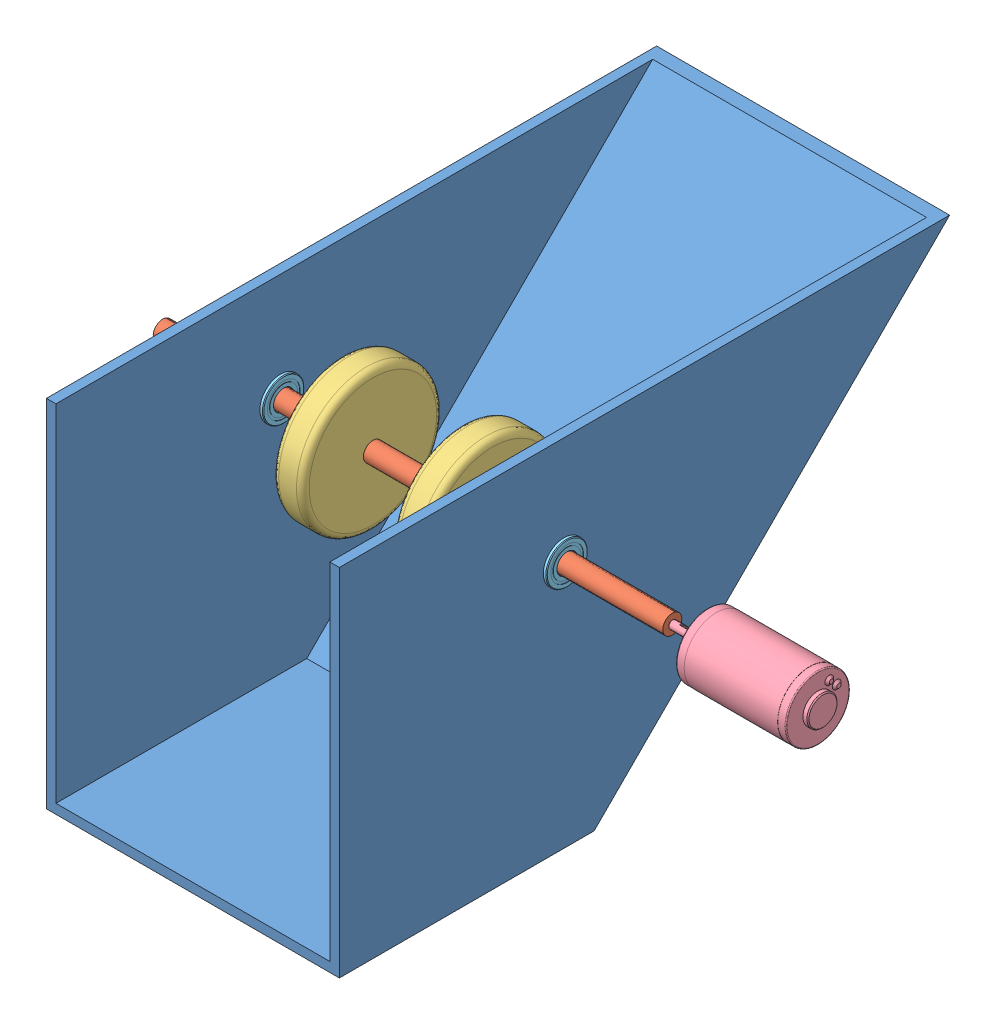
SolidWorks assembly Launcher1, configuration Default. Lengths in mm.
Overall size (658.2 354.41 608.41).
7 component instances, 5 part files, 12 mates.
Components (placement in the parent):
- WheelAndSurfaceBase-1: WheelAndSurfaceBase [Default] at origin size (292.1 354.41 608.41)
- LauncherAxel-1: LauncherAxel [Default] at (0 56.9612 93.5173) x (0 0.196579 -0.980488) z (0 0.980488 0.196579) size (19 508 19)
- 5.5Wheel-1: 5.5Wheel [Default] at (-59.69 56.9612 93.5173) x (0 0.971322 0.237769) z (0 -0.237769 0.971322) size (139.7 30.48 139.7)
- 5.5Wheel-2: 5.5Wheel [Default] at (59.69 56.9612 93.5173) x (0 0.997812 -0.066119) z (0 0.066119 0.997812) size (139.7 30.48 139.7)
- CIM-217-2000-3580300-1: CIM-217-2000-3580300 [Default] at (289.6 56.9612 93.5173) size (150.2 64.01 64.01)
- FlangeBearing-1: FlangeBearing [6384K367] at (-140.4938 56.9612 93.5173) x (0 0 -1) z (1 0 0) size (44.45 44.45 14.29)
- FlangeBearing-3: FlangeBearing [6384K367] at (142.0812 56.9612 93.5173) x (0 0 -1) z (1 0 0) size (44.45 44.45 14.29)
Mates (geometry in assembly coordinates):
- Concentric1: concentric anti-aligned: cylinder of LauncherAxel-1 through (-254 56.9612 93.5173) axis (1 0 0) radius 9.4996; cylinder of 5.5Wheel-1 through (-44.45 56.9612 93.5173) axis (-1 0 0) radius 9.525
- Concentric2: concentric anti-aligned: cylinder of LauncherAxel-1 through (-254 56.9612 93.5173) axis (1 0 0) radius 9.4996; cylinder of 5.5Wheel-2 through (74.93 56.9612 93.5173) axis (-1 0 0) radius 9.525
- Concentric8: concentric anti-aligned: cylinder of WheelAndSurfaceBase-1 through (368.046 56.9612 93.5173) axis (-1 0 0) radius 20.6375; cylinder of LauncherAxel-1 through (-254 56.9612 93.5173) axis (1 0 0) radius 9.4996
- Distance1: distance = 88.9 mm anti-aligned: plane of 5.5Wheel-1 through (-44.45 56.9612 93.5173) normal (1 0 0); plane of 5.5Wheel-2 through (44.45 56.9612 93.5173) normal (-1 0 0)
- Width1: width aligned: plane of WheelAndSurfaceBase-1 through (136.525 190.5 317.5) normal (-1 0 0); plane of WheelAndSurfaceBase-1 through (-136.525 190.5 317.5) normal (1 0 0); plane of 5.5Wheel-1 through (-74.93 56.9612 93.5173) normal (-1 0 0); plane of 5.5Wheel-2 through (74.93 56.9612 93.5173) normal (1 0 0)
- Width2: width anti-aligned: plane of LauncherAxel-1 through (254 56.9612 93.5173) normal (1 0 0); plane of LauncherAxel-1 through (-254 56.9612 93.5173) normal (-1 0 0); plane of WheelAndSurfaceBase-1 through (-146.05 190.5 317.5) normal (-1 0 0); plane of WheelAndSurfaceBase-1 through (146.05 190.5 317.5) normal (1 0 0)
- Tangent3: tangent: plane of LauncherAxel-1 through (254 56.9612 93.5173) normal (1 0 0); circle of CIM-217-2000-3580300-1
- Concentric9: concentric aligned: cylinder of LauncherAxel-1 through (-254 56.9612 93.5173) axis (1 0 0) radius 9.4996; cylinder of CIM-217-2000-3580300-1 through (289.6 56.9612 93.5173) axis (1 0 0) radius 32.004
- Concentric10: concentric anti-aligned: cylinder of WheelAndSurfaceBase-1 through (368.046 56.9612 93.5173) axis (-1 0 0) radius 20.6375; cylinder of FlangeBearing-1 through (-133.35 56.9612 93.5173) axis (1 0 0) radius 20.6375
- Tangent4: tangent: plane of WheelAndSurfaceBase-1 through (-146.05 190.5 317.5) normal (-1 0 0); circle of FlangeBearing-1
- Concentric19: concentric anti-aligned: cylinder of WheelAndSurfaceBase-1 through (368.046 56.9612 93.5173) axis (-1 0 0) radius 20.6375; cylinder of FlangeBearing-3 through (149.225 56.9612 93.5173) axis (1 0 0) radius 20.6375
- Tangent17: tangent: circle of WheelAndSurfaceBase-1; plane of FlangeBearing-3 through (136.525 73.2287 93.5173) normal (1 0 0)
